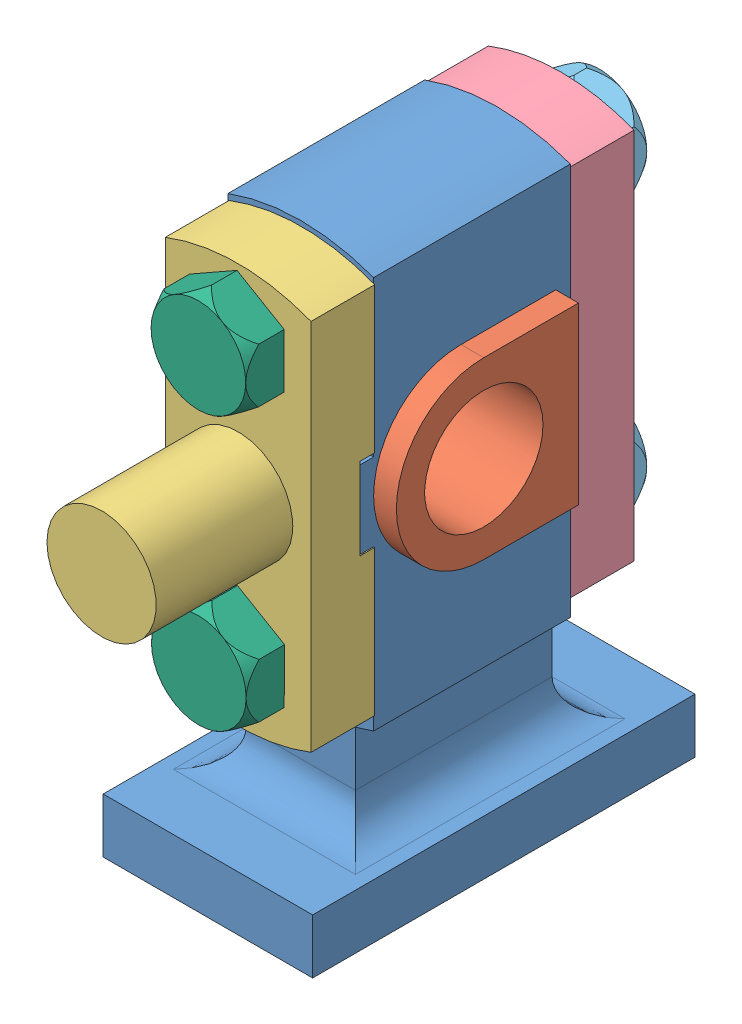
SolidWorks assembly Crosshead Assembly, configuration Default. Lengths in mm.
Overall size (115 306.02 276.33).
8 component instances, 6 part files, 11 mates.
Components (placement in the parent):
- Body-1: Body [Default] at (33.1546 183.8839 261.2442) size (115 306.02 210)
- Bushing-1: Bushing [Default] at (-19.3454 187.8659 267.2442) x (1 0 0) z (0 0 -1) size (105 96 100)
- Bracket-2: Bracket [Default] at (33.7567 186.1897 315.2442) x (0 1 0) z (1 0 0) size (220 110 80)
- Front-Plate-1: Front-Plate [Default] at (33.1546 187.8659 172.2442) x (0 1 0) z (0 0 1) size (220 80 35)
- Nut-1: Nut [Default] at (33.1546 262.8659 151.2442) size (55.64 63.62 22.21)
- Nut-2: Nut [Default] at (33.1546 112.8659 151.2442) size (55.64 63.62 22.21)
- Bolt-1: Bolt [Default] at (33.1546 262.8659 350.4704) size (55.58 63.62 222.33)
- Bolt-3: Bolt [Default] at (33.1546 112.8659 350.2442) size (55.58 63.62 222.33)
Mates (geometry in assembly coordinates):
- Concentric5: concentric aligned: cylinder of Body-1 through (558.8436 187.8659 267.2442) axis (-1 0 0) radius 40; cylinder of Bushing-1 through (73.1546 187.8659 267.2442) axis (-1 0 0) radius 40
- Coincident4: coincident anti-aligned: plane of Body-1 through (73.1546 183.8839 315.2442) normal (1 0 0); plane of Bushing-1 through (73.1546 187.8659 267.2442) normal (-1 0 0)
- Coincident8: coincident anti-aligned: plane of Body-1 through (33.1546 183.8839 323.2442) normal (0 0 1); plane of Bracket-2 through (33.7567 186.1897 323.2442) normal (0 0 -1)
- Coincident9: coincident anti-aligned: plane of Body-1 through (33.1546 183.8839 315.2442) normal (0 0 1); plane of Bracket-2 through (33.7567 186.1897 315.2442) normal (0 0 -1)
- Coincident10: coincident anti-aligned: plane of Body-1 through (33.1546 183.8839 315.2442) normal (0 0 1); plane of Bracket-2 through (33.7567 186.1897 315.2442) normal (0 0 -1)
- Coincident11: coincident aligned: circle of Body-1; circle of Front-Plate-1
- Coincident12: coincident aligned: circle of Front-Plate-1; circle of Nut-1
- Coincident13: coincident aligned: circle of Front-Plate-1; circle of Nut-2
- Concentric9: concentric aligned: cylinder of Body-1 through (33.1546 262.8659 156.2442) axis (0 0 1) radius 15; cylinder of Bolt-1 through (33.1546 262.8659 150.4704) axis (0 0 1) radius 15
- Concentric11: concentric aligned: cylinder of Body-1 through (33.1546 112.8659 156.2442) axis (0 0 1) radius 15; cylinder of Bolt-3 through (33.1546 112.8659 150.2442) axis (0 0 1) radius 15
- Coincident14: coincident anti-aligned: plane of Bracket-2 through (33.7567 186.1897 350.2442) normal (0 0 1); plane of Bolt-3 through (33.1546 112.8659 350.2442) normal (0 0 -1)
